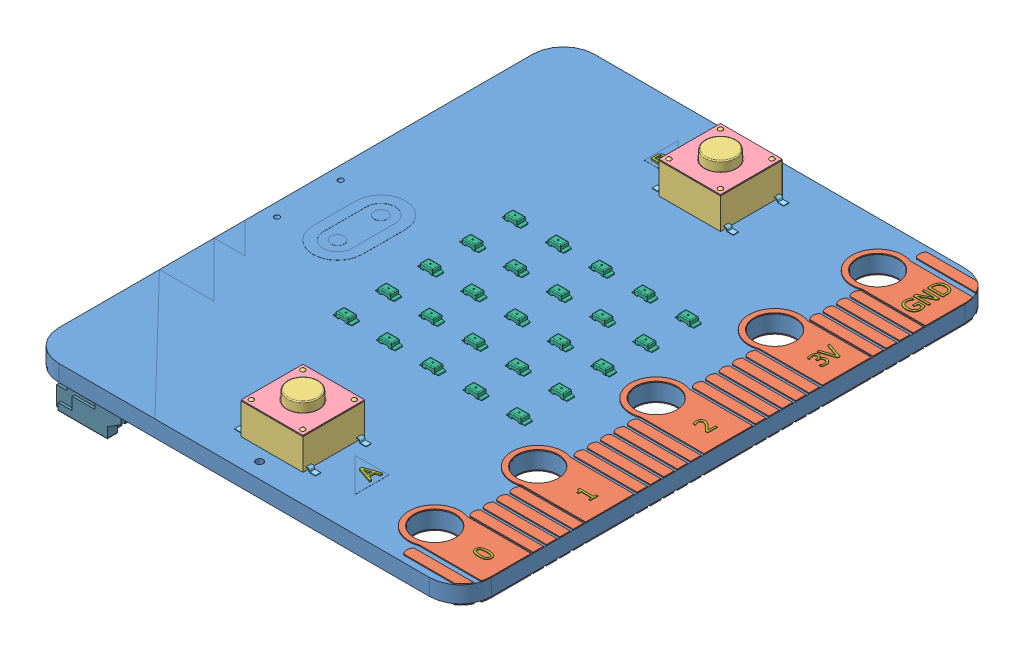
SolidWorks assembly micro bit v1, configuration Défaut. Lengths in mm.
Overall size (42.75 10.6 52.08).
130 component instances, 21 part files, 0 mates.
Components (placement in the parent):
- microbit main board-1: microbit main board [Défaut] at (-3.2777 0.4763 0) size (42.08 1.68 52.08)
- Pins-1: Pins [Défaut] at (-3.2777 2.0763 0) x (-1 0 0) z (0 1 0) size (9.5 50.77 0.1)
- Pins-2: Pins [Défaut] at (-3.2777 0.3763 0.0058) x (-1 0 0) z (0 1 0) size (9.5 50.77 0.1)
- Button assembly microbit-1: Button assembly microbit [Défaut] at (-21.275 4.3857 5.1467) x (-0.001808 0 -0.999998) z (-0.999998 0 0.001808) size (7.86 4 6)
  - Button black part-1: Button black part [Défaut] at (-4.8715 3.9094 0) size (6 4 6)
  - Button metal plate-1: Button metal plate [Défaut] at (-4.8715 6.9094 0) x (-1 0 0) z (0 1 0) size (5.98 5.98 0.1)
  - feet-1: feet [Défaut] at (-7.8615 3.9094 2.7) size (7.86 0.32 5.4)
- Button assembly microbit-2: Button assembly microbit [Défaut] at (1.6265 -1.8332 -20.2125) size (7.86 4 6)
  - Button black part-1: Button black part [Défaut] at (-4.8715 3.9094 0) size (6 4 6)
  - Button metal plate-1: Button metal plate [Défaut] at (-4.8715 6.9094 0) x (-1 0 0) z (0 1 0) size (5.98 5.98 0.1)
  - feet-1: feet [Défaut] at (-7.8615 3.9094 2.7) size (7.86 0.32 5.4)
- Button assembly microbit-3: Button assembly microbit [Défaut] at (1.5965 -1.8332 20.3016) size (7.86 4 6)
  - Button black part-1: Button black part [Défaut] at (-4.8715 3.9094 0) size (6 4 6)
  - Button metal plate-1: Button metal plate [Défaut] at (-4.8715 6.9094 0) x (-1 0 0) z (0 1 0) size (5.98 5.98 0.1)
  - feet-1: feet [Défaut] at (-7.8615 3.9094 2.7) size (7.86 0.32 5.4)
- LED-1: LED [Défaut] at (-11.1022 2.0763 8.2807) size (1.81 0.5 0.81)
- LED-2: LED [Défaut] at (-6.9022 2.0763 8.2807) size (1.81 0.5 0.81)
- LED-3: LED [Défaut] at (-2.7022 2.0763 8.2807) size (1.81 0.5 0.81)
- LED-4: LED [Défaut] at (1.4978 2.0763 8.2807) size (1.81 0.5 0.81)
- LED-5: LED [Défaut] at (5.6978 2.0763 8.2807) size (1.81 0.5 0.81)
- LED-6: LED [Défaut] at (-11.1022 2.0763 4.1807) size (1.81 0.5 0.81)
- LED-7: LED [Défaut] at (-6.9022 2.0763 4.1807) size (1.81 0.5 0.81)
- LED-8: LED [Défaut] at (-2.7022 2.0763 4.1807) size (1.81 0.5 0.81)
- LED-9: LED [Défaut] at (1.4978 2.0763 4.1807) size (1.81 0.5 0.81)
- LED-10: LED [Défaut] at (5.6978 2.0763 4.1807) size (1.81 0.5 0.81)
- LED-11: LED [Défaut] at (-11.1022 2.0763 0.0807) size (1.81 0.5 0.81)
- LED-12: LED [Défaut] at (-6.9022 2.0763 0.0807) size (1.81 0.5 0.81)
- LED-13: LED [Défaut] at (-2.7022 2.0763 0.0807) size (1.81 0.5 0.81)
- LED-14: LED [Défaut] at (1.4978 2.0763 0.0807) size (1.81 0.5 0.81)
- LED-15: LED [Défaut] at (5.6978 2.0763 0.0807) size (1.81 0.5 0.81)
- LED-16: LED [Défaut] at (-11.1022 2.0763 -4.0193) size (1.81 0.5 0.81)
- LED-17: LED [Défaut] at (-6.9022 2.0763 -4.0193) size (1.81 0.5 0.81)
- LED-18: LED [Défaut] at (-2.7022 2.0763 -4.0193) size (1.81 0.5 0.81)
- LED-19: LED [Défaut] at (1.4978 2.0763 -4.0193) size (1.81 0.5 0.81)
- LED-20: LED [Défaut] at (5.6978 2.0763 -4.0193) size (1.81 0.5 0.81)
- LED-21: LED [Défaut] at (-11.1022 2.0763 -8.1193) size (1.81 0.5 0.81)
- LED-22: LED [Défaut] at (-6.9022 2.0763 -8.1193) size (1.81 0.5 0.81)
- LED-23: LED [Défaut] at (-2.7022 2.0763 -8.1193) size (1.81 0.5 0.81)
- LED-24: LED [Défaut] at (1.4978 2.0763 -8.1193) size (1.81 0.5 0.81)
- LED-25: LED [Défaut] at (5.6978 2.0763 -8.1193) size (1.81 0.5 0.81)
- Front face text-1: Front face text [Défaut] at (-3.2777 2.0763 0) x (-1 0 0) z (0 1 0) size (25.96 45.67 0.15)
- Chip one-1: Chip one [Défaut] at (-13.0723 0.4763 -16.7101) x (1 0 0) z (0 0 -1) size (6.58 0.8 6.58)
- Chip two-1: Chip two [Défaut] at (-11.2753 0.4763 16.1469) x (1 0 0) z (0 0 -1) size (5.76 0.8 5.76)
- Chip three-1: Chip three [Défaut] at (0.4992 0.4763 -21.4808) x (1 0 0) z (0 0 -1) size (2.79 0.8 2.79)
- Chip three-2: Chip three [Défaut] at (5.61 0.4763 -19.9193) x (1 0 0) z (0 0 -1) size (2.79 0.8 2.79)
- chip four-1: chip four [Défaut] at (-9.8852 0.4763 21.2616) x (1 0 0) z (0 0 -1) size (2 0.3 2.5)
- chip four-2: chip four [Défaut] at (-15.6186 0.4763 -24.6791) x (-0.003241 0 -0.999995) z (-0.999995 0 0.003241) size (2 0.3 2.5)
- chip five-1: chip five [Défaut] at (-17.9736 0.4763 -1.8324) x (1 0 0) z (0 0 -1) size (1.5 0.6 1.31)
- micro usb-1: micro usb [Défaut] at (-4.1411 0.4763 0.3666) x (-0.000489 0 1) z (0 -1 0) size (7.43 4.87 2)
- JST connector-1: JST connector [Défaut] at (-4.7543 0.4763 1.3649) x (0.000874 0 1) z (0 -1 0) size (7.5 6.5 5)
- Circle capacitors-1: Circle capacitors [Défaut] at (0.1471 0.3763 5.1339) x (1 0 0) z (0 1 0) size (1.2 1.2 0.1)
- Circle capacitors-2: Circle capacitors [Défaut] at (0.1471 0.3763 8.1339) x (1 0 0) z (0 1 0) size (1.2 1.2 0.1)
- Circle capacitors-3: Circle capacitors [Défaut] at (0.1471 0.3763 11.1339) x (1 0 0) z (0 1 0) size (1.2 1.2 0.1)
- Circle capacitors-4: Circle capacitors [Défaut] at (0.1471 0.3763 14.1339) x (1 0 0) z (0 1 0) size (1.2 1.2 0.1)
- Circle capacitors-5: Circle capacitors [Défaut] at (0.1471 0.3763 17.1339) x (1 0 0) z (0 1 0) size (1.2 1.2 0.1)
- Circle capacitors-6: Circle capacitors [Défaut] at (7.6355 0.3763 13.0092) x (1 0 0) z (0 1 0) size (1.2 1.2 0.1)
- Circle capacitors-7: Circle capacitors [Défaut] at (7.6355 0.3763 16.0092) x (1 0 0) z (0 1 0) size (1.2 1.2 0.1)
- Circle capacitors-8: Circle capacitors [Défaut] at (-18.5015 0.3763 -14.7764) x (1 0 0) z (0 1 0) size (1.2 1.2 0.1)
- Circle capacitors-9: Circle capacitors [Défaut] at (-15.5015 0.3763 -14.7764) x (1 0 0) z (0 1 0) size (1.2 1.2 0.1)
- Circle capacitors-10: Circle capacitors [Défaut] at (-18.5015 0.3763 -11.7764) x (1 0 0) z (0 1 0) size (1.2 1.2 0.1)
- Circle capacitors-11: Circle capacitors [Défaut] at (-15.5015 0.3763 -11.7764) x (1 0 0) z (0 1 0) size (1.2 1.2 0.1)
- Resistor-1: Resistor [Défaut] at (4.0942 0.4763 -24.1419) x (0.002395 0 -0.999997) z (-0.999997 0 -0.002395) size (1 0.5 0.5)
- Resistor-2: Resistor [Défaut] at (5.0942 0.4763 -24.1395) x (0.002395 0 -0.999997) z (-0.999997 0 -0.002395) size (1 0.5 0.5)
- Resistor-3: Resistor [Défaut] at (6.0942 0.4763 -24.1371) x (0.002395 0 -0.999997) z (-0.999997 0 -0.002395) size (1 0.5 0.5)
- Resistor-4: Resistor [Défaut] at (-17.2357 0.4763 -23.2369) x (0.005186 0 -0.999987) z (-0.999987 0 -0.005186) size (1 0.5 0.5)
- Resistor-5: Resistor [Défaut] at (-17.2434 0.4763 -21.7369) x (0.005186 0 -0.999987) z (-0.999987 0 -0.005186) size (1 0.5 0.5)
- Resistor-6: Resistor [Défaut] at (-17.2512 0.4763 -20.2369) x (0.005186 0 -0.999987) z (-0.999987 0 -0.005186) size (1 0.5 0.5)
- Resistor-7: Resistor [Défaut] at (-17.259 0.4763 -18.737) x (0.005186 0 -0.999987) z (-0.999987 0 -0.005186) size (1 0.5 0.5)
- Resistor-8: Resistor [Défaut] at (-18.0418 0.4763 -14.024) x (0.002689 0 -0.999996) z (-0.999996 0 -0.002689) size (1 0.5 0.5)
- Resistor-9: Resistor [Défaut] at (-17.3418 0.4763 -14.0221) x (0.002689 0 -0.999996) z (-0.999996 0 -0.002689) size (1 0.5 0.5)
- Back text-1: Back text [Défaut] at (-3.2777 0.4763 0) x (1 0 0) z (0 -1 0) size (28.69 42.15 0.02)
- back face lines-1: back face lines [Défaut] at (-3.2777 0.4763 0) x (1 0 0) z (0 -1 0) size (28.96 50.19 0.02)
- antenna-1: antenna [Défaut] at (-21.1152 0.5763 -17.5407) x (1 0 0) z (0 -1 0) size (5.5 12.5 0.1)
- Slot capacitors-1: Slot capacitors [Défaut] at (-3.2777 0.4763 0) x (1 0 0) z (0 -1 0) size (16.46 1.26 0.1)
- Assembly2-1: Assembly2 [Défaut] at (1.8392 0 3.5908) size (1 0.5 5)
  - Resistor-1: Resistor [Défaut] at (-1.9054 0.4763 9.2437) x (1 0 0) z (0 0 -1) size (1 0.5 0.5)
  - Resistor-2: Resistor [Défaut] at (-1.9054 0.4763 10.7437) x (1 0 0) z (0 0 -1) size (1 0.5 0.5)
  - Resistor-3: Resistor [Défaut] at (-1.9054 0.4763 12.2437) x (1 0 0) z (0 0 -1) size (1 0.5 0.5)
  - Resistor-4: Resistor [Défaut] at (-1.9054 0.4763 13.7437) x (1 0 0) z (0 0 -1) size (1 0.5 0.5)
- Resistor-10: Resistor [Défaut] at (-1.5976 -0.0237 -24.771) size (1 0.5 0.5)
- Resistor-11: Resistor [Défaut] at (3.7063 0.4763 -21.2556) x (-0.005842 0 -0.999983) z (-0.999983 0 0.005842) size (1 0.5 0.5)
- Resistor-12: Resistor [Défaut] at (5.0618 0.4763 -17.5697) x (1 0 0) z (0 0 -1) size (1 0.5 0.5)
- Resistor-13: Resistor [Défaut] at (-8.5506 0.4763 -13.9406) x (1 0 0) z (0 0 -1) size (1 0.5 0.5)
- Resistor-14: Resistor [Défaut] at (4.371 0.4763 -15.0928) x (1 0 0) z (0 0 -1) size (1 0.5 0.5)
- Resistor-15: Resistor [Défaut] at (-8.3479 0.4763 -19.7762) x (1 0 0) z (0 0 -1) size (1 0.5 0.5)
- Resistor-16: Resistor [Défaut] at (-9.2757 0.4763 -21.2717) x (1 0 0) z (0 0 -1) size (1 0.5 0.5)
- Resistor-17: Resistor [Défaut] at (-12.2637 0.4763 -24.605) x (1 0 0) z (0 0 -1) size (1 0.5 0.5)
- Resistor-18: Resistor [Défaut] at (-0.0193 0.4763 -24.7275) x (1 0 0) z (0 0 -1) size (1 0.5 0.5)
- Resistor-19: Resistor [Défaut] at (5.4639 0.4763 -14.3447) x (1 0 0) z (0 0 -1) size (1 0.5 0.5)
- Resistor-20: Resistor [Défaut] at (4.385 0.4763 -15.996) x (1 0 0) z (0 0 -1) size (1 0.5 0.5)
- Resistor-21: Resistor [Défaut] at (2.8052 0.4763 -24.567) x (1 0 0) z (0 0 -1) size (1 0.5 0.5)
- Resistor-22: Resistor [Défaut] at (-6.9918 0.4763 -12.4293) x (1 0 0) z (0 0 -1) size (1 0.5 0.5)
- Resistor-23: Resistor [Défaut] at (-18.0667 0.4763 -19.8277) x (0.001784 0 -0.999998) z (-0.999998 0 -0.001784) size (1 0.5 0.5)
- Resistor-24: Resistor [Défaut] at (-17.7657 0.4763 -24.972) x (1 0 0) z (0 0 -1) size (1 0.5 0.5)
- Resistor-25: Resistor [Défaut] at (-16.8089 0.4763 -0.5884) x (1 0 0) z (0 0 -1) size (1 0.5 0.5)
- Resistor-26: Resistor [Défaut] at (-18.2385 0.4763 5.4996) x (1 0 0) z (0 0 -1) size (1 0.5 0.5)
- Resistor-27: Resistor [Défaut] at (6.0671 0.4763 16.4227) x (0.003334 0 0.999994) z (0.999994 0 -0.003334) size (1 0.5 0.5)
- Resistor-28: Resistor [Défaut] at (7.2335 0.4763 8.8773) x (-0.017635 0 0.999844) z (0.999844 0 0.017635) size (1 0.5 0.5)
- Resistor-29: Resistor [Défaut] at (-12.1963 0.4763 -0.2082) x (1 0 0) z (0 0 -1) size (1 0.5 0.5)
- Resistor-30: Resistor [Défaut] at (-12.3977 0.4763 -2.323) x (1 0 0) z (0 0 -1) size (1 0.5 0.5)
- Resistor-31: Resistor [Défaut] at (-10.3378 0.4763 -11.3694) x (1 0 0) z (0 0 -1) size (1 0.5 0.5)
- Resistor-32: Resistor [Défaut] at (-7.0053 0.4763 -13.9267) x (1 0 0) z (0 0 -1) size (1 0.5 0.5)
- Resistor-33: Resistor [Défaut] at (-8.7734 0.4763 -12.7358) x (1 0 0) z (0 0 -1) size (1 0.5 0.5)
- Resistor-34: Resistor [Défaut] at (-18.0375 0.4763 -23.2354) x (0.001185 0 -0.999999) z (-0.999999 0 -0.001185) size (1 0.5 0.5)
- Resistor-35: Resistor [Défaut] at (-15.8758 0.4763 -22.3625) x (-0.010541 0 -0.999944) z (-0.999944 0 0.010541) size (1 0.5 0.5)
- Resistor-36: Resistor [Défaut] at (-18.0579 0.4763 -15.5415) x (-0.006757 0 -0.999977) z (-0.999977 0 0.006757) size (1 0.5 0.5)
- Resistor-37: Resistor [Défaut] at (-17.0121 0.4763 0.3288) x (1 0 0) z (0 0 -1) size (1 0.5 0.5)
- Resistor-38: Resistor [Défaut] at (-6.5659 0.4763 15.4968) x (1 0 0) z (0 0 -1) size (1 0.5 0.5)
- Resistor-39: Resistor [Défaut] at (-13.5797 0.4763 24.5207) x (1 0 0) z (0 0 -1) size (1 0.5 0.5)
- Resistor-40: Resistor [Défaut] at (-18.1284 0.4763 24.5763) x (1 0 0) z (0 0 -1) size (1 0.5 0.5)
- Resistor-41: Resistor [Défaut] at (-13.5874 0.4763 20.0872) x (1 0 0) z (0 0 -1) size (1 0.5 0.5)
- Resistor-42: Resistor [Défaut] at (-11.9799 0.4763 19.5307) x (1 0 0) z (0 0 -1) size (1 0.5 0.5)
- Resistor-43: Resistor [Défaut] at (-13.601 0.4763 20.9587) x (1 0 0) z (0 0 -1) size (1 0.5 0.5)
- Resistor-44: Resistor [Défaut] at (6.8908 0.4763 21.0202) x (0.00342 0 0.999994) z (0.999994 0 -0.00342) size (1 0.5 0.5)
- Resistor-45: Resistor [Défaut] at (-7.0266 0.4763 14.7504) x (1 0 0) z (0 0 -1) size (1 0.5 0.5)
- Circle capacitors-12: Circle capacitors [Défaut] at (-4.5127 0.4763 -3.362) x (1 0 0) z (0 -1 0) size (1.2 1.2 0.1)
- Circle capacitors-13: Circle capacitors [Défaut] at (-4.9129 0.3763 12.1979) x (1 0 0) z (0 1 0) size (1.2 1.2 0.1)
- Circle capacitors-14: Circle capacitors [Défaut] at (-20.8154 0.3763 -13.2232) x (1 0 0) z (0 1 0) size (1.2 1.2 0.1)
- Circle capacitors-15: Circle capacitors [Défaut] at (-13.613 0.3763 -0.5314) x (1 0 0) z (0 1 0) size (1.2 1.2 0.1)
- Circle capacitors-16: Circle capacitors [Défaut] at (-13.4021 0.3763 -5.1092) x (1 0 0) z (0 1 0) size (1.2 1.2 0.1)
- Circle capacitors-17: Circle capacitors [Défaut] at (-9.9203 0.3763 14.3756) x (1 0 0) z (0 1 0) size (1.2 1.2 0.1)
- Circle capacitors-18: Circle capacitors [Défaut] at (-5.0055 0.3763 17.1824) x (1 0 0) z (0 1 0) size (1.2 1.2 0.1)
- Circle capacitors-19: Circle capacitors [Défaut] at (2.8952 0.3763 17.0291) x (1 0 0) z (0 1 0) size (1.2 1.2 0.1)
- Circle capacitors-20: Circle capacitors [Défaut] at (-0.1101 0.3763 -12.538) x (1 0 0) z (0 1 0) size (1.2 1.2 0.1)
- Capacitor-1: Capacitor [Défaut] at (-12.469 0.5263 7.8747) size (1 0.5 0.5)
- Capacitor-2: Capacitor [Défaut] at (-14.09 0.4763 10.8955) x (1 0 0) z (0 0 -1) size (1 0.5 0.5)
- Capacitor-3: Capacitor [Défaut] at (-7.7315 0.4763 -18.9984) x (1 0 0) z (0 0 -1) size (1 0.5 0.5)
- Capacitor-4: Capacitor [Défaut] at (-7.9242 0.4763 21.4426) x (1 0 0) z (0 0 -1) size (1 0.5 0.5)
- Capacitor-5: Capacitor [Défaut] at (-9.7099 0.4763 10.945) x (1 0 0) z (0 0 -1) size (1 0.5 0.5)
- Capacitor-6: Capacitor [Défaut] at (-15.5072 0.4763 15.0976) x (1 0 0) z (0 0 -1) size (1 0.5 0.5)
